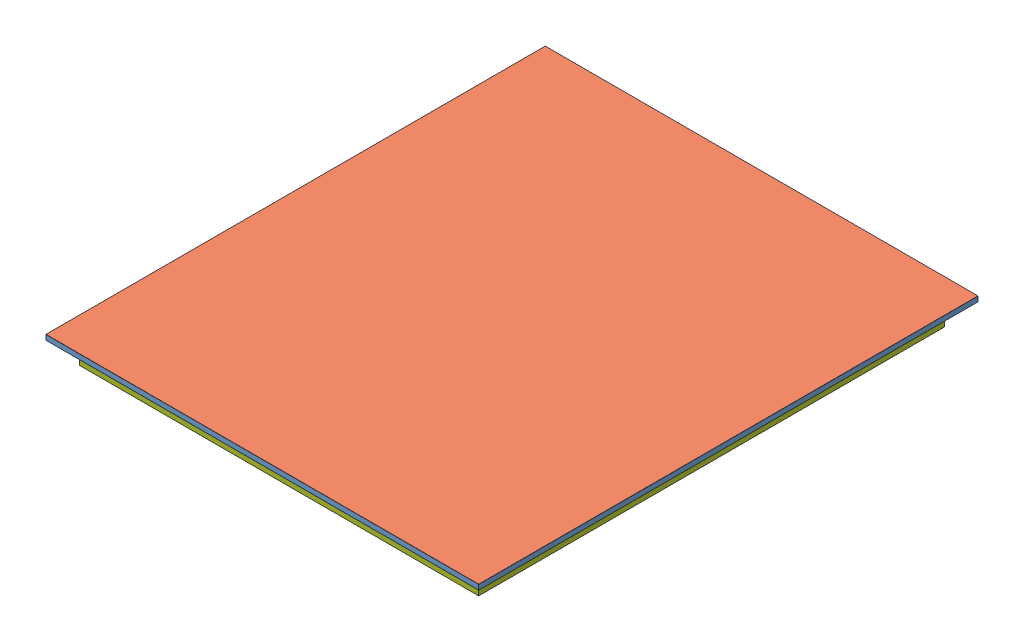
SolidWorks assembly Ukaz, configuration По умолчанию. Lengths in mm.
Overall size (336.15 16.1 512.38).
7 component instances, 7 part files, 16 mates.
Components (placement in the parent):
- org_steklo-1: org_steklo [По умолчанию] at (250.2711 294.0368 335.619) size (336.15 10 512.38)
- plenka-1: plenka [По умолчанию] at (250.2711 304.0368 335.619) x (-1 0 0) z (0 1 0) size (260 300 0.1)
- vladish-1: vladish [По умолчанию] at (156.6602 296.0368 428.2395) x (0 1 0) z (0 0 1) size (8 15.6 15.6)
- plata_pravo_verh-1: plata_pravo_verh [По умолчанию] at (255.2711 294.0368 412.619) size (160 1.5 60)
- plata_sered-1: plata_sered [По умолчанию] at (250.2711 294.0368 312.619) size (160 1.5 100)
- plata_nizhn-1: plata_nizhn [По умолчанию] at (262.2711 294.0368 229.119) size (100 1.5 25)
- penopolisterol-1: penopolisterol [По умолчанию] at (250.2711 288.0368 335.619) x (0 0 -1) z (1 0 0) size (360.02 6 286.67)
Mates (geometry in assembly coordinates):
- Совпадение1: coincident anti-aligned: plane of org_steklo-1 through (250.2711 304.0368 335.619) normal (0 1 0); plane of plenka-1 through (250.2711 304.0368 335.619) normal (0 -1 0)
- Совпадение3: coincident aligned: plane of org_steklo-1 through (120.2711 304.0368 485.619) normal (0 0 1); plane of plenka-1 through (120.2711 304.1368 485.619) normal (0 0 1)
- Совпадение4: coincident aligned: plane of org_steklo-1 through (120.2711 304.0368 185.619) normal (-1 0 0); plane of plenka-1 through (120.2711 304.1368 185.619) normal (-1 0 0)
- Совпадение6: coincident aligned: plane of org_steklo-1 through (250.2711 296.0368 335.619) normal (0 -1 0); plane of vladish-1 through (156.6602 296.0368 428.2395) normal (0 -1 0)
- Расстояние5: distance = 23 mm anti-aligned: plane of plata_pravo_verh-1 through (175.2711 295.5368 442.619) normal (0 0 1); plane of org_steklo-1 through (360.2711 296.0368 465.619) normal (0 0 -1)
- Расстояние6: distance = 103 mm anti-aligned: plane of plata_sered-1 through (170.2711 295.5368 362.619) normal (0 0 1); plane of org_steklo-1 through (360.2711 296.0368 465.619) normal (0 0 -1)
- Совпадение14: coincident aligned: plane of org_steklo-1 through (250.2711 294.0368 335.619) normal (0 -1 0); plane of plata_sered-1 through (250.2711 294.0368 312.619) normal (0 -1 0)
- Расстояние7: distance = 30 mm anti-aligned: plane of plata_sered-1 through (330.2711 295.5368 262.619) normal (1 0 0); plane of org_steklo-1 through (360.2711 296.0368 205.619) normal (-1 0 0)
- Расстояние8: distance = 11 mm: plane of plata_nizhn-1 through (212.2711 295.5368 216.619) normal (0 0 -1); line of org_steklo-1 through (140.2711 294.0368 205.619) axis (1 0 0)
- Совпадение18: coincident aligned: plane of org_steklo-1 through (250.2711 294.0368 335.619) normal (0 -1 0); plane of plata_nizhn-1 through (262.2711 294.0368 229.119) normal (0 -1 0)
- Расстояние9: distance = 48 mm anti-aligned: plane of plata_nizhn-1 through (312.2711 295.5368 216.619) normal (1 0 0); plane of org_steklo-1 through (360.2711 296.0368 205.619) normal (-1 0 0)
- Совпадение19: coincident aligned: plane of org_steklo-1 through (250.2711 294.0368 335.619) normal (0 -1 0); plane of plata_pravo_verh-1 through (255.2711 294.0368 412.619) normal (0 -1 0)
- Расстояние10: distance = 35 mm anti-aligned: plane of plata_pravo_verh-1 through (175.2711 295.5368 382.619) normal (-1 0 0); plane of org_steklo-1 through (140.2711 296.0368 205.619) normal (1 0 0)
- Совпадение21: coincident anti-aligned: plane of org_steklo-1 through (250.2711 294.0368 335.619) normal (0 -1 0); plane of penopolisterol-1 through (250.2711 294.0368 335.619) normal (0 1 0)
- Концентричный1: concentric anti-aligned: cylinder of org_steklo-1 through (365.2711 294.0368 200.619) axis (0 -1 0) radius 1.25; cylinder of penopolisterol-1 through (365.2711 294.0368 200.619) axis (0 1 0) radius 1.55
- Концентричный2: concentric anti-aligned: cylinder of org_steklo-1 through (365.2711 294.0368 470.619) axis (0 -1 0) radius 1.25; cylinder of penopolisterol-1 through (365.2711 294.0368 470.619) axis (0 1 0) radius 1.55
